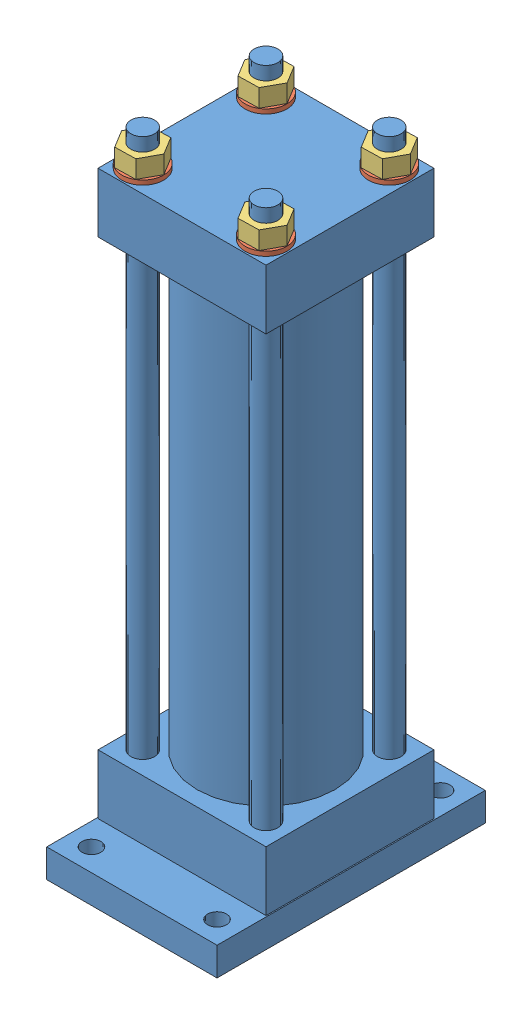
SolidWorks assembly Ensamblaje piston, configuration Predeterminado. Lengths in mm.
Overall size (114.3 421.05 180).
9 component instances, 3 part files, 16 mates.
Components (placement in the parent):
- base de piston-1: base de piston [Predeterminado] at (-81.3698 -203.2076 421.05) size (114.3 421.05 180)
- rondana de 16mm-1: rondana de 16mm [Predeterminado] at (-122.726 193.8424 462.4062) size (28 3 28)
- rondana de 16mm-2: rondana de 16mm [Predeterminado] at (-122.726 193.8424 379.6938) size (28 3 28)
- rondana de 16mm-3: rondana de 16mm [Predeterminado] at (-40.0135 193.8424 462.4062) x (0.999451 0 0.033137) z (-0.033137 0 0.999451) size (28 3 28)
- rondana de 16mm-4: rondana de 16mm [Predeterminado] at (-40.0135 193.8424 379.6938) size (28 3 28)
- tuerca de 16mm-1: tuerca de 16mm [Predeterminado] at (-40.0135 196.8424 462.4062) size (27.71 12 24.32)
- tuerca de 16mm-2: tuerca de 16mm [Predeterminado] at (-40.0135 196.8424 379.6938) size (27.71 12 24.32)
- tuerca de 16mm-3: tuerca de 16mm [Predeterminado] at (-122.726 196.8424 462.4062) size (27.71 12 24.32)
- tuerca de 16mm-4: tuerca de 16mm [Predeterminado] at (-122.726 196.8424 379.6938) size (27.71 12 24.32)
Mates (geometry in assembly coordinates):
- Concéntrica1: concentric: cylinder of base de piston-1 through (-122.726 217.8424 462.4062) axis (0 -1 0) radius 8; cylinder of rondana de 16mm-1 through (-122.726 196.8424 462.4062) axis (0 -1 0) radius 8
- Coincidente1: coincident anti-aligned: plane of base de piston-1 through (-81.3698 193.8424 421.05) normal (0 1 0); plane of rondana de 16mm-1 through (-122.726 193.8424 462.4062) normal (0 -1 0)
- Concéntrica2: concentric aligned: cylinder of base de piston-1 through (-122.726 217.8424 379.6938) axis (0 -1 0) radius 8; cylinder of rondana de 16mm-2 through (-122.726 196.8424 379.6938) axis (0 -1 0) radius 8
- Coincidente2: coincident anti-aligned: plane of base de piston-1 through (-81.3698 193.8424 421.05) normal (0 1 0); plane of rondana de 16mm-2 through (-122.726 193.8424 379.6938) normal (0 -1 0)
- Concéntrica3: concentric aligned: cylinder of base de piston-1 through (-40.0135 217.8424 462.4062) axis (0 -1 0) radius 8; cylinder of rondana de 16mm-3 through (-40.0135 196.8424 462.4062) axis (0 -1 0) radius 8
- Coincidente3: coincident anti-aligned: plane of base de piston-1 through (-81.3698 193.8424 421.05) normal (0 1 0); plane of rondana de 16mm-3 through (-40.0135 193.8424 462.4062) normal (0 -1 0)
- Concéntrica4: concentric aligned: cylinder of base de piston-1 through (-40.0135 217.8424 379.6938) axis (0 -1 0) radius 8; cylinder of rondana de 16mm-4 through (-40.0135 198.3424 379.6938) axis (0 -1 0) radius 8
- Coincidente4: coincident aligned: plane of rondana de 16mm-2 through (-122.726 196.8424 379.6938) normal (0 1 0); plane of rondana de 16mm-4 through (-40.0135 196.8424 379.6938) normal (0 1 0)
- Concéntrica5: concentric aligned: cylinder of base de piston-1 through (-40.0135 217.8424 462.4062) axis (0 -1 0) radius 8; cylinder of tuerca de 16mm-1 through (-40.0135 208.8424 462.4062) axis (0 -1 0) radius 8
- Coincidente5: coincident anti-aligned: plane of rondana de 16mm-3 through (-40.0135 196.8424 462.4062) normal (0 1 0); plane of tuerca de 16mm-1 through (-40.0135 196.8424 462.4062) normal (0 -1 0)
- Concéntrica6: concentric aligned: cylinder of base de piston-1 through (-40.0135 217.8424 379.6938) axis (0 -1 0) radius 8; cylinder of tuerca de 16mm-2 through (-40.0135 208.8424 379.6938) axis (0 -1 0) radius 8
- Coincidente6: coincident aligned: plane of tuerca de 16mm-1 through (-40.0135 208.8424 462.4062) normal (0 1 0); plane of tuerca de 16mm-2 through (-40.0135 208.8424 379.6938) normal (0 1 0)
- Concéntrica7: concentric aligned: cylinder of base de piston-1 through (-122.726 217.8424 462.4062) axis (0 -1 0) radius 8; cylinder of tuerca de 16mm-3 through (-122.726 208.8424 462.4062) axis (0 -1 0) radius 8
- Coincidente7: coincident aligned: plane of tuerca de 16mm-1 through (-40.0135 208.8424 462.4062) normal (0 1 0); plane of tuerca de 16mm-3 through (-122.726 208.8424 462.4062) normal (0 1 0)
- Concéntrica8: concentric aligned: cylinder of base de piston-1 through (-122.726 217.8424 379.6938) axis (0 -1 0) radius 8; cylinder of tuerca de 16mm-4 through (-122.726 214.8424 379.6938) axis (0 -1 0) radius 8
- Coincidente8: coincident aligned: plane of tuerca de 16mm-3 through (-122.726 208.8424 462.4062) normal (0 1 0); plane of tuerca de 16mm-4 through (-122.726 208.8424 379.6938) normal (0 1 0)
